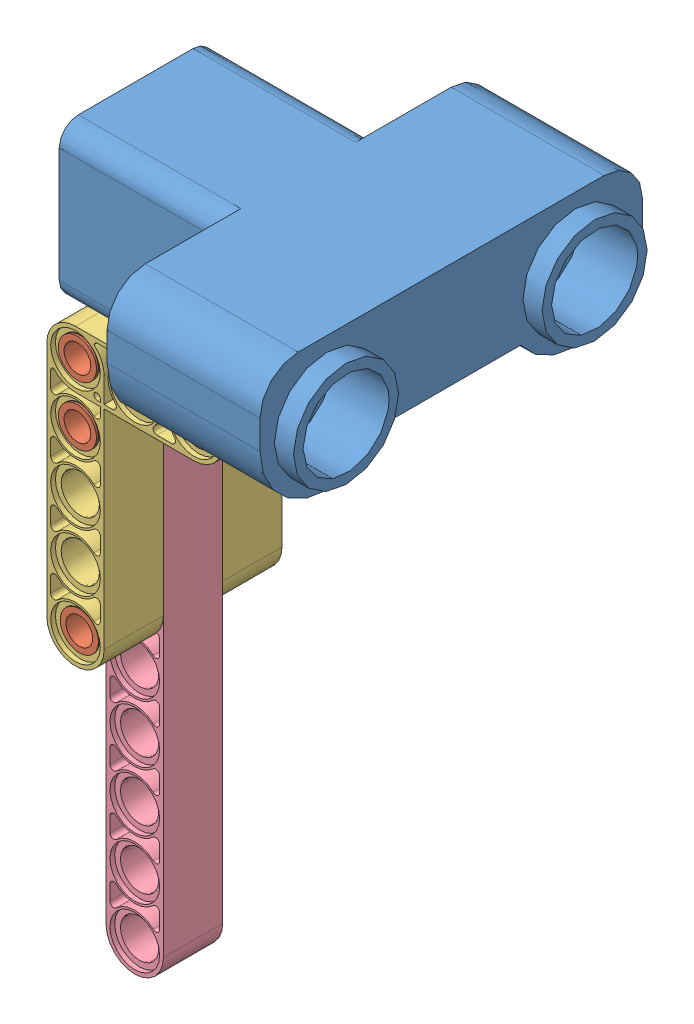
SolidWorks assembly head, configuration Default. Lengths in mm.
Overall size (44.45 98.81 50.8).
8 component instances, 4 part files, 23 mates.
Components (placement in the parent):
- ProximitySensor-1: ProximitySensor [Default] x (1 0 0) z (0 1 0) size (44.45 50.8 27.94)
- BlueConnectorLong-3: BlueConnectorLong [Default] at (-17.5045 0 10.8063) x (0 0 -1) z (0 -1 0) size (22.86 5.59 5.59)
- BlueConnectorLong-4: BlueConnectorLong [Default] at (-1.7565 0 -12.3077) x (0 0 1) z (1 0 0) size (22.86 5.59 5.59)
- L_Three_Five_90degrees-1: L_Three_Five_90degrees [Default] at (-17.5045 -7.874 10.8063) x (0 1 0) z (0 0 -1) size (39.12 23.37 7.87)
- L_Three_Five_90degrees-3: L_Three_Five_90degrees [Default] at (-17.5045 -7.874 -4.9417) x (0 1 0) z (0 0 -1) size (39.12 23.37 7.87)
- BlueConnectorLong-5: BlueConnectorLong [Default] at (-17.5045 -7.874 10.8063) x (0 0 -1) z (1 0 0) size (22.86 5.59 5.59)
- BlueConnectorLong-6: BlueConnectorLong [Default] at (-17.5045 -31.496 -12.3077) x (0 0 1) z (0 -1 0) size (22.86 5.59 5.59)
- All_Straight-2: All_Straight [Nine] at (-17.5045 -15.748 -4.6877) x (0 1 0) z (0 0 1) size (70.61 7.62 7.87)
Mates (geometry in assembly coordinates):
- Coincident1: coincident aligned: plane of ProximitySensor-1 through (0 0 0) normal (0 1 0); plane of assembly through (0 0 0) normal (0 1 0)
- Coincident2: coincident anti-aligned: plane of ProximitySensor-1 through (0 0 0) normal (0 0 -1); plane of assembly through (0 0 0) normal (0 0 1)
- Coincident3: coincident aligned: plane of ProximitySensor-1; plane of assembly through (0 0 0) normal (1 0 0)
- Concentric12: concentric aligned: cylinder of BlueConnectorLong-3 through (-17.5045 0 10.8063) axis (0 0 1) radius 2.032; cylinder of L_Three_Five_90degrees-1 through (-17.5045 0 6.9963) axis (0 0 1) radius 2.54
- Coincident26: coincident anti-aligned: plane of BlueConnectorLong-3 through (-14.7105 0 3.8213) normal (0 0 1); plane of L_Three_Five_90degrees-1 through (-17.5045 0 3.8213) normal (0 0 -1)
- Concentric13: concentric aligned: cylinder of L_Three_Five_90degrees-1 through (-17.5045 -7.874 6.9963) axis (0 0 1) radius 2.54; cylinder of BlueConnectorLong-5 through (-17.5045 -7.874 10.8063) axis (0 0 1) radius 2.032
- Coincident27: coincident anti-aligned: plane of L_Three_Five_90degrees-1 through (-17.5045 -7.874 3.8213) normal (0 0 -1); plane of BlueConnectorLong-5 through (-17.5045 -5.08 3.8213) normal (0 0 1)
- Concentric14: concentric anti-aligned: cylinder of BlueConnectorLong-5 through (-17.5045 -7.874 10.8063) axis (0 0 1) radius 2.032; cylinder of All_Straight-2 through (-17.5045 -7.874 -0.7507) axis (0 0 -1) radius 2.54
- Coincident28: coincident anti-aligned: plane of BlueConnectorLong-5 through (-17.5045 -5.842 2.5513) normal (0 0 -1); plane of All_Straight-2 through (-17.5045 -7.874 2.5513) normal (0 0 1)
- Concentric15: concentric aligned: cylinder of BlueConnectorLong-6 through (-17.5045 -31.496 -12.3077) axis (0 0 -1) radius 2.032; cylinder of All_Straight-2 through (-17.5045 -31.496 -0.7507) axis (0 0 -1) radius 2.54
- Coincident29: coincident anti-aligned: plane of BlueConnectorLong-6 through (-19.5365 -31.496 -4.0527) normal (0 0 1); plane of All_Straight-2 through (-17.5045 -31.496 -4.0527) normal (0 0 -1)
- Concentric16: concentric anti-aligned: cylinder of L_Three_Five_90degrees-1 through (-17.5045 -31.496 6.9963) axis (0 0 1) radius 2.54; cylinder of BlueConnectorLong-6 through (-17.5045 -31.496 -12.3077) axis (0 0 -1) radius 2.032
- Concentric17: concentric anti-aligned: cylinder of L_Three_Five_90degrees-3 through (-17.5045 -31.496 -8.7517) axis (0 0 1) radius 2.54; cylinder of BlueConnectorLong-6 through (-17.5045 -31.496 -12.3077) axis (0 0 -1) radius 2.032
- Coincident30: coincident anti-aligned: plane of L_Three_Five_90degrees-3 through (-17.5045 -31.496 -5.3227) normal (0 0 1); plane of BlueConnectorLong-6 through (-20.2985 -31.496 -5.3227) normal (0 0 -1)
- Concentric18: concentric anti-aligned: cylinder of BlueConnectorLong-4 through (-1.7565 0 -12.3077) axis (0 0 -1) radius 2.032; cylinder of L_Three_Five_90degrees-3 through (-1.7565 0 -8.7517) axis (0 0 1) radius 2.54
- Coincident31: coincident anti-aligned: plane of BlueConnectorLong-4 through (-1.7565 -2.794 -5.3227) normal (0 0 -1); plane of L_Three_Five_90degrees-3 through (-1.7565 0 -5.3227) normal (0 0 1)
- Concentric19: concentric aligned: cylinder of ProximitySensor-1 through (-1.7565 0 -0.7507) axis (0 0 -1) radius 2.54; cylinder of BlueConnectorLong-4 through (-1.7565 0 -12.3077) axis (0 0 -1) radius 2.032
- Concentric20: concentric anti-aligned: cylinder of ProximitySensor-1 through (-17.5045 0 -0.7507) axis (0 0 -1) radius 2.54; cylinder of BlueConnectorLong-3 through (-17.5045 0 10.8063) axis (0 0 1) radius 2.032
- Width1: width anti-aligned: plane of L_Three_Five_90degrees-1 through (-40.189 -7.874 11.0603) normal (0 0 1); plane of L_Three_Five_90degrees-3 through (-40.189 -7.874 -12.5617) normal (0 0 -1); plane of ProximitySensor-1 through (0.2755 19.05 -26.1507) normal (0 0 -1); plane of ProximitySensor-1 through (0.2755 19.05 24.6493) normal (0 0 1)
- Parallel3: parallel anti-aligned: plane of BlueConnectorLong-3 through (-17.5045 0 10.8063) normal (0 -1 0); plane of assembly through (0 0 0) normal (0 1 0)
- Parallel4: parallel anti-aligned: plane of BlueConnectorLong-4; plane of assembly through (0 0 0) normal (0 1 0)
- Parallel5: parallel aligned: plane of BlueConnectorLong-5; plane of assembly through (0 0 0) normal (0 1 0)
- Parallel6: parallel anti-aligned: plane of BlueConnectorLong-6 through (-17.5045 -31.496 -12.3077) normal (0 -1 0); plane of assembly through (0 0 0) normal (0 1 0)
